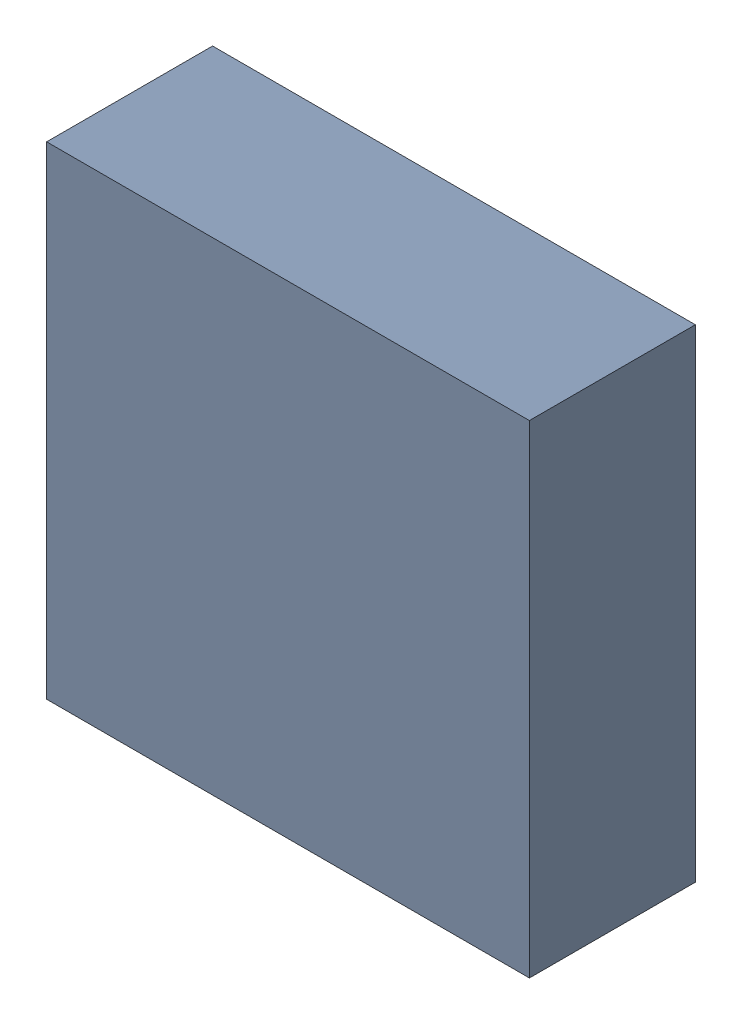
SolidWorks assembly U302_1PCB, configuration Default. Lengths in mm.
Overall size (3.2 3.2 1.1).
2 component instances, 1 part files, 0 mates.
Components (placement in the parent):
- 846484240-1: 846484240 [Default] at (140.9 117.3 0) size (3.2 3.2 1.1)
  - Extruded_11-1: Extruded_11 [Default] at origin size (3.2 3.2 1.1)
